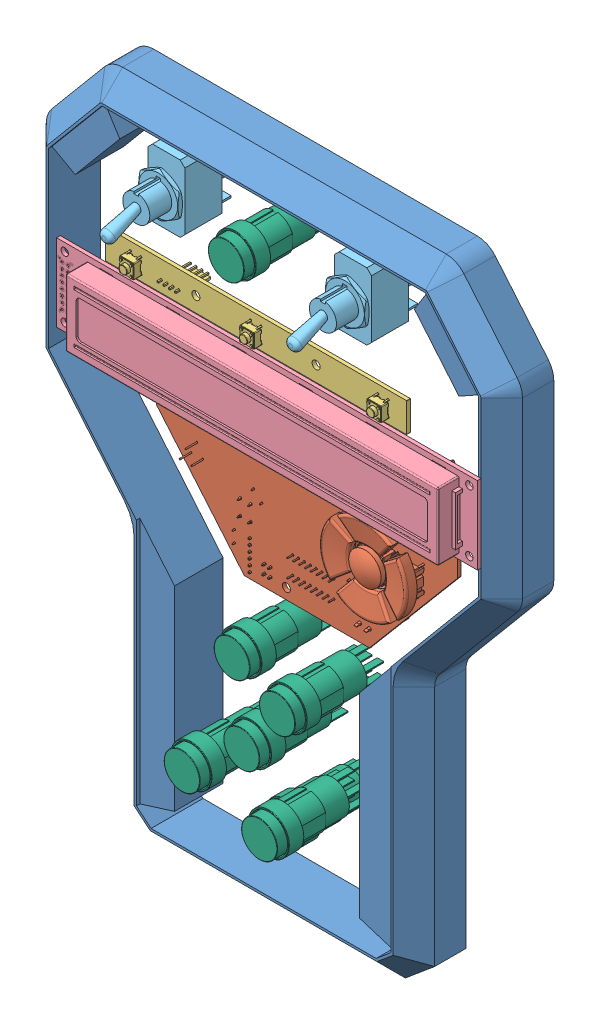
SolidWorks assembly Montagem005.2, configuration Valor predeterminado. Lengths in mm.
Overall size (206 280 68.1).
13 component instances, 6 part files, 1 mates.
Components (placement in the parent):
- 5 - TEC02 - Moldura-1: 5 - TEC02 - Moldura [Valor predeterminado] at (-14.3479 -136.6702 -11.25) size (206 280 22.5)
- PCB_IHM-1: PCB_IHM [Valor predeterminado] at (-42.5483 -21.3236 -8.6761) size (130.25 70.25 27.35)
- PCB_IHM_Teclas_Superiores-1: PCB_IHM_Teclas_Superiores [Valor predeterminado] at (-78.5012 90.559 15.34) size (130.25 12.75 19.2)
- LCD Display 4002-1: LCD Display 4002 [Valor predeterminado] at (-11.0193 69.5319 8.5441) size (182 33.5 13.65)
- BCV3 112 103 - Controle chave geral-1: BCV3 112 103 - Controle chave geral [Default] at (-57.6578 124.5296 2) size (17 29 51.5)
- BCV3 112 103 - Controle chave geral-2: BCV3 112 103 - Controle chave geral [Default] at (23.0755 124.5296 2) size (17 29 51.5)
- BCV3 112 102 - Controle botão-1: BCV3 112 102 - Controle botão [Valor predeterminado] at (-28.0821 -35.0634 0.85) x (1 0 0) z (0 -1 0) size (17.7 39.7 17.7)
- BCV3 112 102 - Controle botão-2: BCV3 112 102 - Controle botão [Valor predeterminado] at (-11.537 -91.8977 -1.8) x (1 0 0) z (0 -1 0) size (17.7 39.7 17.7)
- BCV3 112 102 - Controle botão-3: BCV3 112 102 - Controle botão [Valor predeterminado] at (2.3466 -35.3921 11.7) x (1 0 0) z (0 -1 0) size (17.7 39.7 17.7)
- BCV3 112 102 - Controle botão-4: BCV3 112 102 - Controle botão [Valor predeterminado] at (-21.1271 122.0762 10.3) x (1 0 0) z (0 -1 0) size (17.7 39.7 17.7)
- BCV3 112 102 - Controle botão-5: BCV3 112 102 - Controle botão [Valor predeterminado] at (-13.0649 -56.2028 11.7) x (1 0 0) z (0 -1 0) size (17.7 39.7 17.7)
- BCV3 112 102 - Controle botão-6: BCV3 112 102 - Controle botão [Valor predeterminado] at (-34.0332 -72.5549 16.5) x (1 0 0) z (0 -1 0) size (17.7 39.7 17.7)
- BCV3 112 102 - Controle botão-7: BCV3 112 102 - Controle botão [Valor predeterminado] at (8.8899 -71.8503 25.95) x (1 0 0) z (0 -1 0) size (17.7 39.7 17.7)
Mates (geometry in assembly coordinates):
- Coincidente2: coincident aligned: plane of 5 - TEC02 - Moldura-1 through (-14.3479 -136.6702 11.25) normal (0 0 1); plane of BCV3 112 102 - Controle botão-1 through (-28.0821 -35.0634 11.25) normal (0 0 1)
